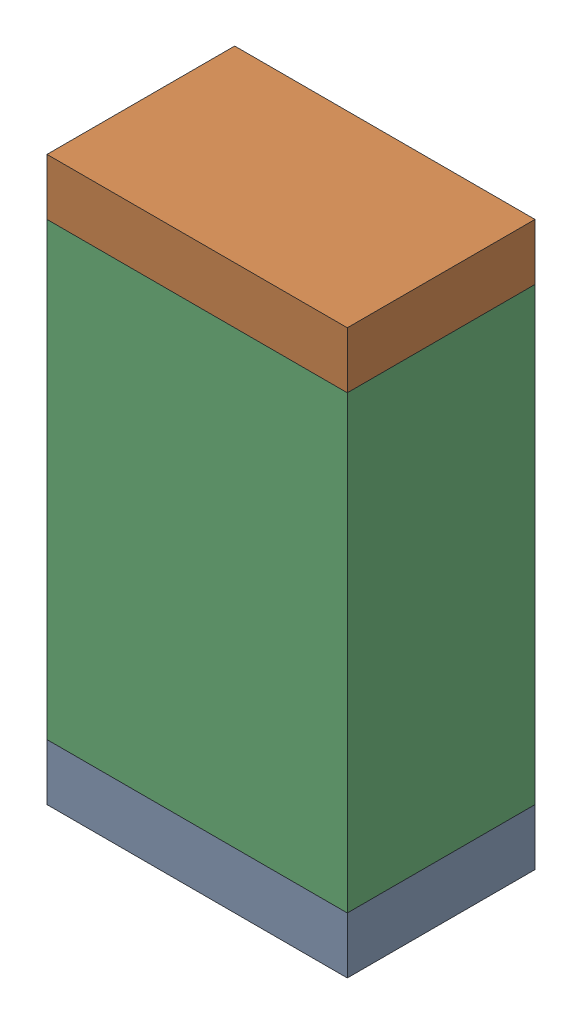
SolidWorks assembly D34, configuration Default. Lengths in mm.
Overall size (0.8 1.5 0.5).
6 component instances, 2 part files, 0 mates.
Components (placement in the parent):
- 810156592-1: 810156592 [Default] at (133.45 78.075 0) size (0.8 0.15 0.5)
  - Extruded_7-1: Extruded_7 [Default] at origin size (0.8 0.15 0.5)
- 810156592-2: 810156592 [Default] at (133.45 79.425 0) size (0.8 0.15 0.5)
  - Extruded_7-1: Extruded_7 [Default] at origin size (0.8 0.15 0.5)
- 810156976-1: 810156976 [Default] at (133.45 78.75 0) size (0.8 1.2 0.5)
  - Extruded_6-1: Extruded_6 [Default] at origin size (0.8 1.2 0.5)
